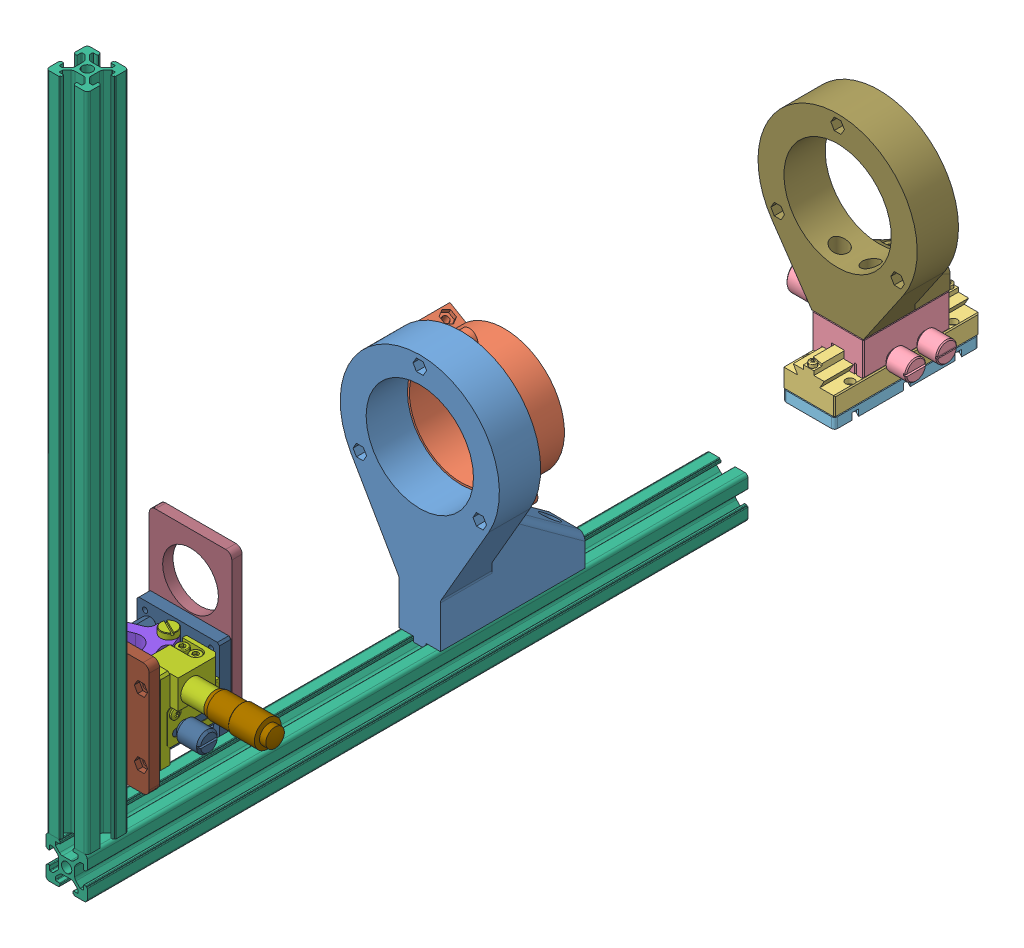
SolidWorks assembly 装配体1, configuration 默认. Lengths in mm.
Overall size (114.65 340 429.36).
16 component instances, 13 part files, 24 mates.
Components (placement in the parent):
- 镜头托架-1: 镜头托架 [默认] at (-2.201 60.7863 5.7559) x (-1 0 0) z (0 1 0) size (77.1 70 122.05)
- 物镜固定架-1: 物镜固定架 [默认] at (-2.201 60.7863 -4.7441) x (-0.866025 0.5 0) z (-0.5 -0.866025 0) size (75.32 21 66.41)
- SLWX25-L70.STEP-1: SLWX25-L70.STEP [默认] at (-2.101 -322.8292 -166.6195) x (0 -1 0) z (-1 0 0) size (26 70 63)
  - LWX25-L70-1.STEP-1: LWX25-L70-1.STEP [默认] at (-316.9155 -65.9089 0) size (17 70 25)
  - LWX25-L50-2.STEP-1: LWX25-L50-2.STEP [默认] at (-317.1155 -30.9089 0) x (0 0 -1) z (0 1 0) size (63 18.5 42)
- 铝型材-滑台-1: 铝型材-滑台 [默认] at (-2.101 -20.2137 -197.5284) x (-1 0 0) z (0 0 -1) size (25 7 70)
- 2020-320-1: 2020-320 [默认] at (-2.201 -30.2137 -123.1737) x (0 -1 0) z (0 0 1) size (20 20 320)
- SLZ40.STEP-1: SLZ40.STEP [默认] at (17.799 6.7337 171.8263) x (1 0 0) z (0 0 -1) size (85.47 41.06 35.18)
  - Z40-1.STEP-1: Z40-1.STEP [默认] at (17.3401 -20 18.2314) x (1 0 0) z (0 -1 0) size (63.5 34.23 40)
  - Z1.STEP-1: Z1.STEP [默认] at (17.3401 -20 18.2314) x (1 0 0) z (0 -1 0) size (27.4 21 10)
  - MT13-1-1.STEP-1: MT13-1-1.STEP [默认] at (17.3401 -19.924 18.0999) x (1 0 0) z (0 -0.999935 0.011399) size (58.5 13.04 13.04)
  - Z40-2.STEP-1: Z40-2.STEP [默认] at (17.3401 -20 18.2314) x (1 0 0) z (0 -1 0) size (52.6 35.18 41.06)
- 升降滑台支架-1: 升降滑台支架 [默认] at (-2.201 26.7337 176.8263) x (1 0 0) z (0 1 0) size (40 7.5 55)
- 2020-320-3: 2020-320 [默认] at (-2.201 -20.2137 186.8263) x (0 0 1) z (0 1 0) size (20 20 320)
- 镜头托架-滑台-1: 镜头托架-滑台 [默认] at (-2.101 60.7863 -196.5284) x (-1 0 0) z (0 1 0) size (77.1 42 88.55)
- 载物台-1: 载物台 [默认] at (-2.201 26.7337 131.8263) x (1 0 0) z (0 -1 0) size (40 5 75)
Mates (geometry in assembly coordinates):
- 重合1: coincident anti-aligned: plane of 铝型材转接板-1 through (-2.201 60.7863 5.7559) normal (0 0 -1); plane of 物镜固定架-1 through (-27.3591 75.3113 5.7559) normal (0 0 1)
- 同心2: concentric anti-aligned: cylinder of 铝型材转接板-1 through (-2.201 60.7863 25.7559) axis (0 0 -1) radius 26; cylinder of 物镜固定架-1 through (-2.201 60.7863 -4.7441) axis (0 0 1) radius 25.05
- 同心3: concentric anti-aligned: cylinder of 铝型材转接板-1 through (-2.201 94.3363 25.7559) axis (0 0 -1) radius 1.8; cylinder of 物镜固定架-1 through (-2.201 94.3363 1.7559) axis (0 0 1) radius 1.65
- 重合2: coincident anti-aligned: plane of SLWX25-L70.STEP-1/LWX25-L70-1.STEP-1 through (-14.601 -15.2137 -232.5284) normal (0 -1 0); plane of 铝型材-滑台-1 through (-2.101 -15.2137 -197.5284) normal (0 1 0)
- 同心4: concentric anti-aligned: cylinder of SLWX25-L70.STEP-1/LWX25-L70-1.STEP-1 through (7.899 -8.4137 -172.5284) axis (0 1 0) radius 2.05; cylinder of 铝型材-滑台-1 through (7.899 -15.2137 -172.5284) axis (0 -1 0) radius 1.3
- 同心5: concentric anti-aligned: cylinder of SLWX25-L70.STEP-1/LWX25-L70-1.STEP-1 through (-12.101 -5.9137 -222.5284) axis (0 1 0) radius 1.25; cylinder of 铝型材-滑台-1 through (-12.101 -15.2137 -222.5284) axis (0 -1 0) radius 1.3
- 重合3: coincident anti-aligned: plane of 铝型材-滑台-1 through (-2.101 -20.2137 -197.5284) normal (0 -1 0); plane of 2020-320-1 through (1.699 -20.2137 196.8263) normal (0 1 0)
- 重合4: coincident anti-aligned: plane of 铝型材-滑台-1 through (0.899 -20.2137 -197.5284) normal (1 0 0); plane of 2020-320-1 through (0.899 -21.7137 196.8263) normal (-1 0 0)
- 重合6: coincident anti-aligned: plane of SLZ40.STEP-1/Z40-1.STEP-1 through (9.799 38.7337 171.8263) normal (0 0 1); plane of 升降滑台支架-1 through (-2.201 26.7337 171.8263) normal (0 0 -1)
- 同心6: concentric aligned: cylinder of SLZ40.STEP-1/Z40-1.STEP-1 through (13.799 10.7337 166.8263) axis (0 0 1) radius 1.75; cylinder of 升降滑台支架-1 through (13.799 10.7337 171.8263) axis (0 0 1) radius 1.65
- 同心7: concentric aligned: cylinder of SLZ40.STEP-1/Z40-1.STEP-1 through (-18.201 42.7337 166.8263) axis (0 0 1) radius 1.75; cylinder of 升降滑台支架-1 through (-18.201 42.7337 171.8263) axis (0 0 1) radius 1.65
- 重合7: coincident anti-aligned: plane of 2020-320-1 through (1.699 -20.2137 196.8263) normal (0 1 0); plane of 2020-320-3 through (-4.2119 -20.2137 192.7263) normal (0 -1 0)
- 重合8: coincident aligned: plane of 2020-320-1 through (-12.201 -26.3137 196.8263) normal (-1 0 0); plane of 2020-320-3 through (-12.201 299.7863 182.9263) normal (-1 0 0)
- 重合9: coincident aligned: plane of 2020-320-1 through (-4.2119 -36.1137 196.8263) normal (0 0 1); plane of 2020-320-3 through (-6.101 299.7863 196.8263) normal (0 0 1)
- 重合10: coincident anti-aligned: plane of 升降滑台支架-1 through (-2.201 26.7337 176.8263) normal (0 0 1); plane of 2020-320-3 through (-10.701 299.7863 176.8263) normal (0 0 -1)
- 重合13: coincident anti-aligned: plane of SLWX25-L70.STEP-1/LWX25-L50-2.STEP-1 through (-14.601 10.7863 -176.5284) normal (0 1 0); plane of 镜头托架-滑台-1 through (-14.601 10.7863 -176.5284) normal (0 -1 0)
- 同心8: concentric anti-aligned: cylinder of SLWX25-L70.STEP-1/LWX25-L50-2.STEP-1 through (5.399 10.7863 -210.0284) axis (0 1 0) radius 1.65; cylinder of 镜头托架-滑台-1 through (5.399 57.7863 -210.0284) axis (0 -1 0) radius 2.15
- 同心9: concentric anti-aligned: cylinder of SLWX25-L70.STEP-1/LWX25-L50-2.STEP-1 through (-9.601 10.7863 -210.0284) axis (0 1 0) radius 1.65; cylinder of 镜头托架-滑台-1 through (-9.601 57.7863 -210.0284) axis (0 -1 0) radius 2.15
- 重合14: coincident anti-aligned: plane of SLZ40.STEP-1/Z40-2.STEP-1 through (-21.701 7.2337 136.8263) normal (0 0 -1); plane of 载物台-1 through (-2.201 26.7337 136.8263) normal (0 0 1)
- 同心10: concentric aligned: cylinder of SLZ40.STEP-1/Z40-2.STEP-1 through (-18.201 10.7337 142.8263) axis (0 0 -1) radius 1.25; cylinder of 载物台-1 through (-18.201 10.7337 136.8263) axis (0 0 -1) radius 1.65
- 同心11: concentric aligned: cylinder of SLZ40.STEP-1/Z40-2.STEP-1 through (13.799 42.7337 142.8263) axis (0 0 -1) radius 1.25; cylinder of 载物台-1 through (13.799 42.7337 136.8263) axis (0 0 -1) radius 1.65
- 重合15: coincident anti-aligned: plane of 镜头托架-1 through (-12.201 -20.2137 25.7559) normal (0 -1 0); plane of 2020-320-1 through (1.699 -20.2137 196.8263) normal (0 1 0)
- 重合17: coincident aligned: plane of 镜头托架-1 through (-12.201 60.7863 5.7559) normal (-1 0 0); plane of 2020-320-1 through (-12.201 -26.3137 196.8263) normal (-1 0 0)
- 距离2: distance = 10 mm aligned: plane of 升降滑台支架-1 through (-22.201 54.2337 171.8263) normal (-1 0 0); plane of 2020-320-3 through (-12.201 299.7863 182.9263) normal (-1 0 0)
